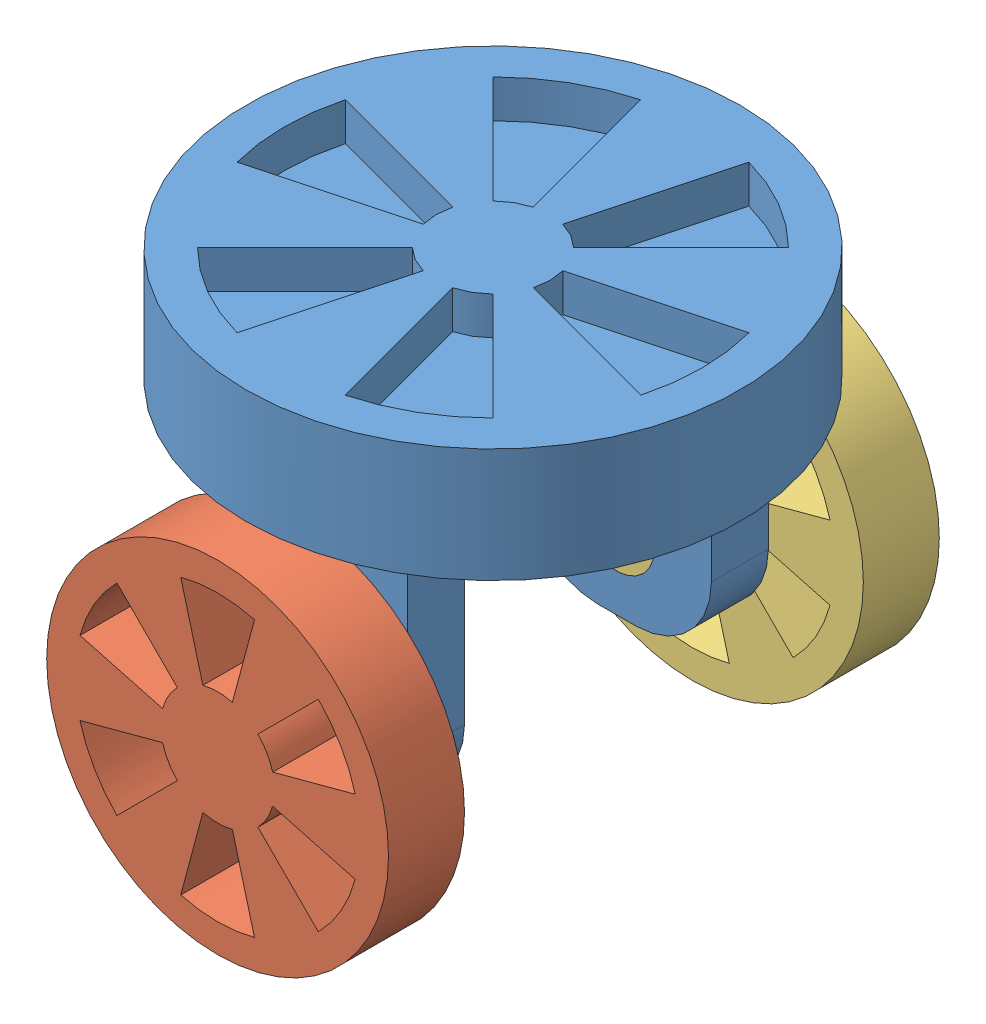
SolidWorks assembly turn_1, configuration 默认. Lengths in mm.
Overall size (130 125 145).
3 component instances, 3 part files, 4 mates.
Components (placement in the parent):
- turntable_1-1: turntable_1 [默认] at (1.3329 19.4764 130) size (130 100 130)
- wheel_1_1-1: wheel_1_1 [默认] at (1.3329 -30.5236 162.5) x (0 0 1) z (-1 0 0) size (40 90 90)
- wheel_1_2-1: wheel_1_2 [默认] at (1.3329 -30.5236 97.5) x (0 0 -1) z (1 0 0) size (40 90 90)
Mates (geometry in assembly coordinates):
- 同心1: concentric: cylinder of turntable_1-1 through (1.3329 -30.5236 65) axis (0 0 1) radius 10; cylinder of ? through (1.3329 -30.5236 215) axis (0 0 -1) radius 10
- 重合1: coincident: plane of assembly; plane of assembly; plane of turntable_1-1 through (-23.6671 -50.5236 162.5) normal (0 0 -1); plane of wheel_1_1-1 through (1.3329 -30.5236 162.5) normal (0 0 -1)
- 同心2: concentric: cylinder of turntable_1-1 through (1.3329 -30.5236 65) axis (0 0 1) radius 10; cylinder of ? through (1.3329 -30.5236 47.8787) axis (0 0 1) radius 10
- 重合2: coincident: plane of assembly; plane of assembly; plane of turntable_1-1 through (-23.6671 -50.5236 97.5) normal (0 0 1); plane of wheel_1_2-1 through (1.3329 -30.5236 97.5) normal (0 0 1)
